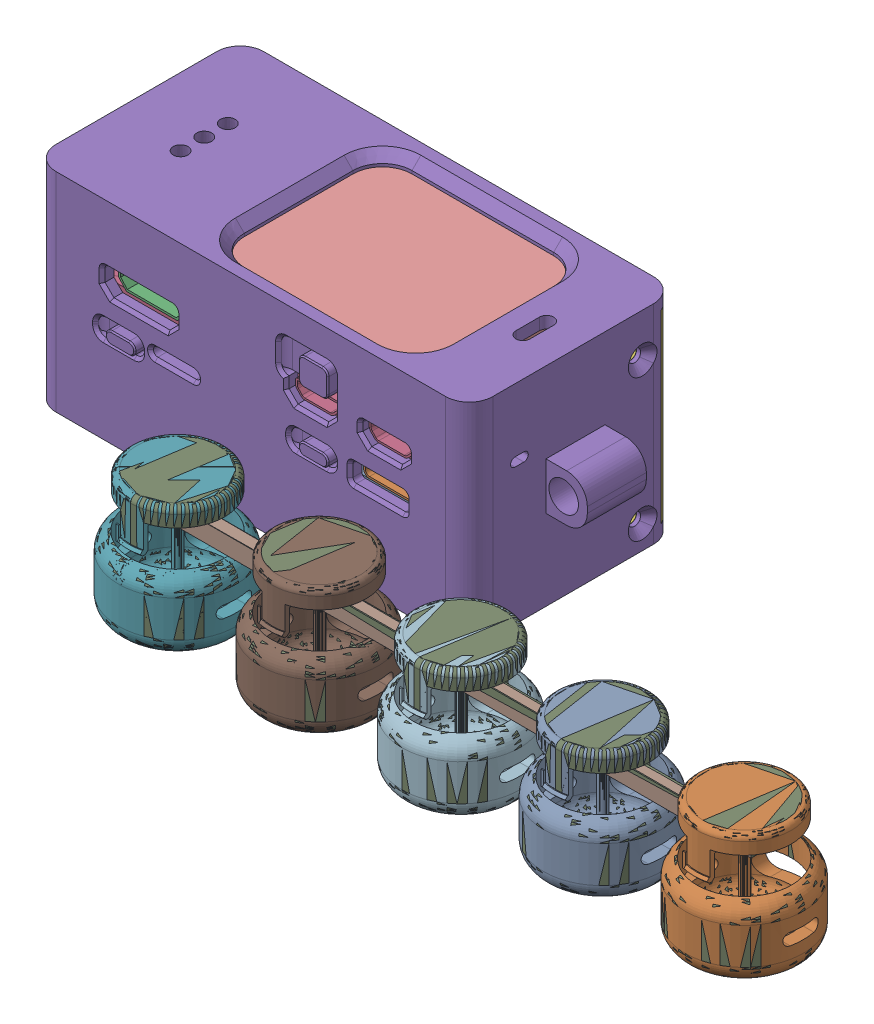
SolidWorks assembly chatbot-comp, configuration 默认. Lengths in mm.
Overall size (81 35.3 35.9).
13 component instances, 9 part files, 12 mates.
Components (placement in the parent):
- battery-1: battery [默认] at (8.9973 -3.3923 -4.242) x (-1 0 0) z (0 0 1) size (60 12.6 28) (hidden)
- pisugar3Board-1: pisugar3Board [Default] at (0.2166 2.0077 0.565) x (-1 0 0) z (0 0 1) size (65 6 30.4) (hidden)
- RaspberryPiZeroWH-1: RaspberryPiZeroWH [Default] at (0.2166 3.5077 0.565) size (65.9 9.4 31.25) (hidden)
- shell-1: shell [默认] at (-17.8336 -13.7221 18.065) x (0 0 -1) z (1 0 0) size (35.9 35.3 81)
- slide-1: slide [默认] at (-6.6963 5.1581 -13.135) x (1 0 0) z (0 1 0) size (74 7.9 31.3)
- button_print-1: button_print [默认] at (9.1743 2.3586 40.3841) size (20 21 20) (hidden)
- button_connect_bar-1: button_connect_bar [默认] at (2.5452 0 3.9027) size (100 3 2) (hidden)
- button_print_batch-1: button_print_batch [默认] at origin size (116 21 20) (hidden)
- whisplay_hat-2: whisplay_hat [默认] at (0.2166 13.4077 0.565) size (65 9.1 30.99) (hidden)
- button_print-2: button_print [默认] at (33.1743 2.3586 40.3841) size (20 21 20) (hidden)
- button_print-3: button_print [默认] at (57.1743 2.3586 40.3841) size (20 21 20) (hidden)
- button_print-4: button_print [默认] at (81.1743 2.3586 40.3841) size (20 21 20) (hidden)
- button_print-5: button_print [默认] at (105.1743 2.3586 40.3841) size (20 21 20) (hidden)
Mates (geometry in assembly coordinates):
- 重合4: coincident anti-aligned: plane of pisugar3Board-1 through (-28.8084 3.5077 -10.96) normal (0 1 0); plane of RaspberryPiZeroWH-1 through (-28.5334 3.5077 -10.685) normal (0 -1 0)
- 距离4: distance = 0.5 mm anti-aligned: plane of RaspberryPiZeroWH-1 through (-28.5334 4.9077 15.565) normal (0 0 1); plane of shell-1 through (-17.8336 -13.7221 16.065) normal (0 0 -1)
- 距离3: distance = 1.5 mm anti-aligned: plane of RaspberryPiZeroWH-1 through (32.7166 4.9077 -10.685) normal (1 0 0); plane of shell-1 through (34.2166 16.6177 16.065) normal (-1 0 0)
- 重合12: coincident aligned: plane of pisugar3Board-1 through (32.7166 1.0077 -10.685) normal (1 0 0); plane of RaspberryPiZeroWH-1 through (32.7166 4.9077 -10.685) normal (1 0 0)
- 重合13: coincident aligned: plane of pisugar3Board-1 through (28.9666 1.0077 15.565) normal (0 0 1); plane of RaspberryPiZeroWH-1 through (-28.5334 4.9077 15.565) normal (0 0 1)
- 同心3: concentric anti-aligned: circle of battery-1; circle of pisugar3Board-1
- 重合14: coincident anti-aligned: plane of battery-1 through (-12.2834 -0.9923 0.565) normal (0 1 0); plane of pisugar3Board-1 through (-12.2834 -0.9923 0.565) normal (0 -1 0)
- 重合19: coincident aligned: plane of shell-1 through (-17.8336 -13.7221 -17.135) normal (0 0 -1); plane of slide-1 through (-6.6963 5.1581 -17.135) normal (0 0 -1)
- 重合20: coincident aligned: line of shell-1 through (-33.7834 16.6177 -17.135) axis (0 1 0); line of slide-1 through (-33.7834 -14.6823 -17.135) axis (0 1 0)
- 重合21: coincident anti-aligned: plane of shell-1 through (-17.8336 -13.7221 15.565) normal (0 0 -1); plane of whisplay_hat-2 through (-28.7834 14.4077 15.565) normal (0 0 1)
- 重合22: coincident aligned: plane of pisugar3Board-1 through (32.7166 1.0077 -10.685) normal (1 0 0); plane of whisplay_hat-2 through (32.7166 14.4077 -10.935) normal (1 0 0)
- 距离5: distance = 8.5 mm anti-aligned: plane of whisplay_hat-2 through (29.2166 13.4077 12.065) normal (0 -1 0); plane of RaspberryPiZeroWH-1 through (-28.5334 4.9077 -10.685) normal (0 1 0)
